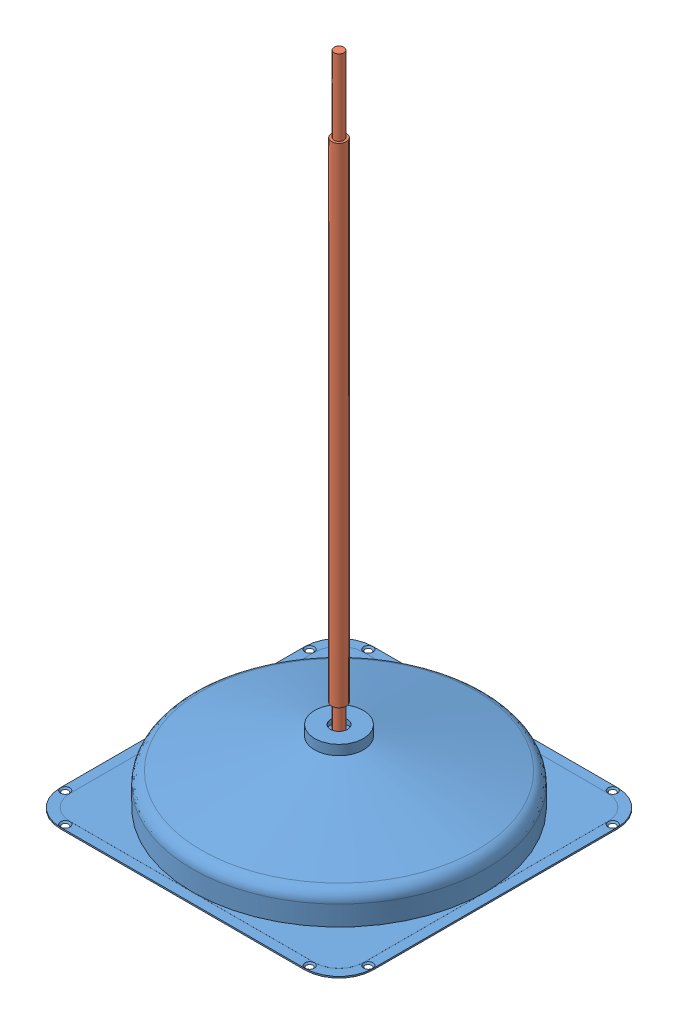
SolidWorks assembly Assem1, configuration Default. Lengths in mm.
Overall size (640 1345 640).
2 component instances, 2 part files, 2 mates.
Components (placement in the parent):
- windturbine onderstel-1: windturbine onderstel [Default] at (207.0504 255.8538 561.1412) size (640 150 640)
- windturbine bovenstuk-1: windturbine bovenstuk [Default] at (207.0504 945.8538 561.1412) x (0.941574 0 -0.336805) z (0.336805 0 0.941574) size (260 1310 260)
Mates (geometry in assembly coordinates):
- Concentric1: concentric: cylinder of windturbine onderstel-1 through (207.0504 405.8538 561.1412) axis (0 1 0) radius 10.3395; cylinder of windturbine bovenstuk-1 through (207.0504 1600.8538 561.1412) axis (0 -1 0) radius 10
- Distance1: distance = 40 mm: plane of windturbine bovenstuk-1 through (207.0504 445.8538 561.1412) normal (0 -1 0); plane of windturbine onderstel-1 through (257.0504 405.8538 561.1412) normal (0 1 0)
